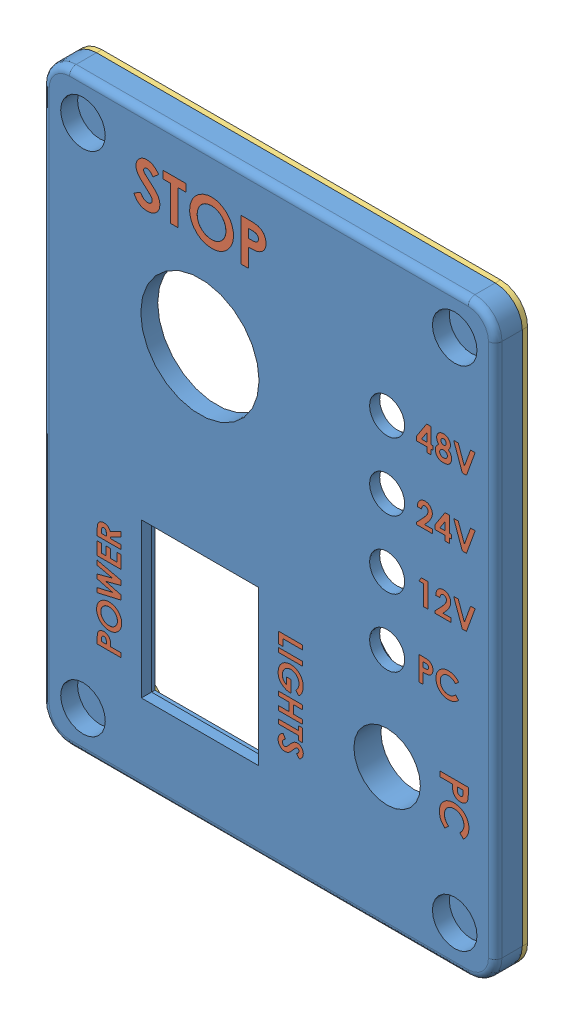
SolidWorks assembly Control Panel, configuration Default. Lengths in mm.
Overall size (85.09 110.49 6.08).
3 component instances, 3 part files, 10 mates.
Components (placement in the parent):
- Control Panel-1: Control Panel [Default] at origin size (85.09 110.49 5.08)
- Control Panel Lettering-1: Control Panel Lettering [Default] at origin size (71.14 83.47 1)
- Panel Cutout Template-1: Panel Cutout Template [Default] at (0 0 -1.905) x (-1 0 0) z (0 0 -1) size (85.09 110.49 1)
Mates (geometry in assembly coordinates):
- Coincident1: coincident aligned: plane of Control Panel-1 through (0 0 0) normal (0 0 1); plane of assembly through (0 0 0) normal (0 0 1)
- Coincident2: coincident aligned: plane of Control Panel-1 through (0 0 0) normal (0 1 0); plane of assembly through (0 0 0) normal (0 1 0)
- Coincident3: coincident aligned: plane of Control Panel-1 through (0 0 0) normal (1 0 0); plane of assembly through (0 0 0) normal (1 0 0)
- Coincident4: coincident aligned: plane of Control Panel Lettering-1 through (0 0 0) normal (0 0 1); plane of assembly through (0 0 0) normal (0 0 1)
- Coincident5: coincident aligned: plane of Control Panel Lettering-1 through (0 0 0) normal (0 1 0); plane of assembly through (0 0 0) normal (0 1 0)
- Coincident6: coincident aligned: plane of Control Panel Lettering-1 through (0 0 0) normal (1 0 0); plane of assembly through (0 0 0) normal (1 0 0)
- InPlace1: in place: plane of ? through (0 0 -1.905) normal (0 0 -1); plane of Panel Cutout Template-1 through (0 0 -1.905) normal (0 0 -1); moOrthogonalPlaneRef_w of ? through (0 0 -1.905) normal (0 0 -1); unknown of Panel Cutout Template-1; plane of ? through (0 0 -1.905) normal (0 0 -1); plane of Panel Cutout Template-1 through (0 0 -1.905) normal (-1 0 0); plane of ? through (0 0 -1.905) normal (0 0 -1); unknown of Panel Cutout Template-1
- Coincident7: coincident aligned: plane of Control Panel-1; plane of Panel Cutout Template-1
- Coincident8: coincident aligned: moOrthogonalPlaneRef_w of Control Panel-1 through (0 0 -1.905) normal (0 1 0); plane of Panel Cutout Template-1
- Coincident9: coincident anti-aligned: moOrthogonalPlaneRef_w of Control Panel-1 through (0 0 -1.905) normal (1 0 0); plane of Panel Cutout Template-1 through (0 0 -1.905) normal (-1 0 0)
